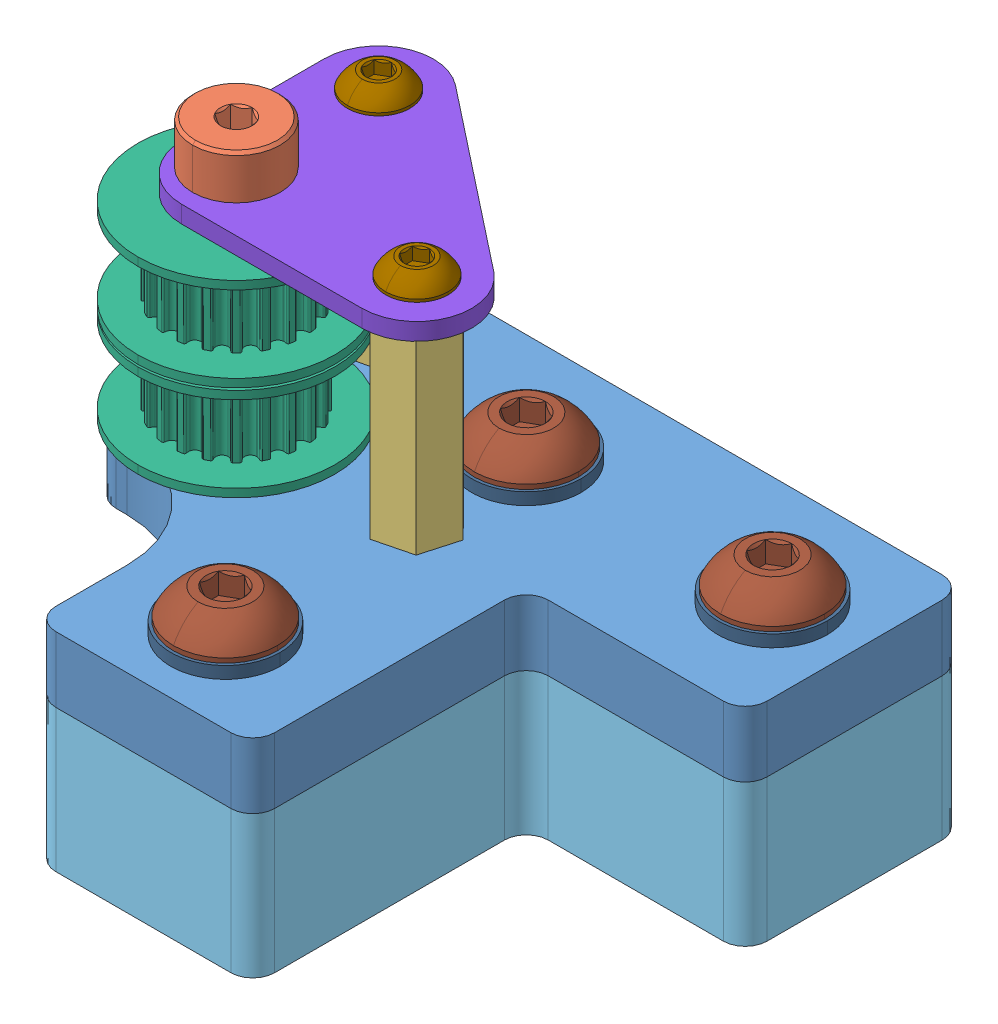
SolidWorks assembly left_double_pulley_corner_bracket_assembly, configuration Default. Lengths in mm.
Overall size (55.5 47.91 45).
24 component instances, 12 part files, 0 mates.
Components (placement in the parent):
- left_double_pulley_corner_bracket_assembly.STEP-1: left_double_pulley_corner_bracket_assembly.STEP [Default] at origin size (55.5 47.91 45)
  - alum_double_pulley_corner_bracketr_Left Double Pulley Corner Bracket.STEP-1: alum_double_pulley_corner_bracketr_Left Double Pulley Corner Bracket.STEP [Default] at (0.7975 43.4223 39.9908) size (53 6 45)
  - m4_shoulder_screw_5mm_d_20mm_l_90278A374_90278A374.STEP-1: m4_shoulder_screw_5mm_d_20mm_l_90278A374_90278A374.STEP [Default] at (7.2975 73.4223 59.9908) x (1 0 0) z (0 1 0) size (8 8 29.01)
  - m3_18mm_hex_standoff_6mm_wide_95947A525_95947A525.STEP-1: m3_18mm_hex_standoff_6mm_wide_95947A525_95947A525.STEP [Default] at (7.2975 58.4223 46.9908) x (0.954641 0 0.297758) z (0 -1 0) size (6 6.93 18)
  - m3_18mm_hex_standoff_6mm_wide_95947A525_95947A525.STEP-2: m3_18mm_hex_standoff_6mm_wide_95947A525_95947A525.STEP [Default] at (23.7975 58.4223 59.9908) x (-0.962053 0 -0.272861) z (0 1 0) size (6 6.93 18)
  - m3_10mm_buttonhead_screw_92095A182_92095A182.STEP-1: m3_10mm_buttonhead_screw_92095A182_92095A182.STEP [Default] at (7.2975 41.7723 46.9908) x (1 0 0) z (0 -1 0) size (5.7 5.7 11.66)
  - m3_10mm_buttonhead_screw_92095A182_92095A182.STEP-2: m3_10mm_buttonhead_screw_92095A182_92095A182.STEP [Default] at (23.7975 41.7723 59.9908) x (1 0 0) z (0 -1 0) size (5.7 5.7 11.66)
  - double_pulley_corner_bracket_Left Machined Bracket Spacer.STEP-1: double_pulley_corner_bracket_Left Machined Bracket Spacer.STEP [Default] at (13.7975 30.4223 84.9908) size (40 13 45)
  - 20t_idler_5mm_bore.STEP-1: 20t_idler_5mm_bore.STEP [Default] at (7.2975 49.6223 59.9908) size (18 8.5 18)
  - 20t_idler_5mm_bore.STEP-2: 20t_idler_5mm_bore.STEP [Default] at (7.2975 58.3223 59.9908) size (18 8.5 18)
  - m5_shim_0.2mm_thick_98089A246_98089A246.STEP-1: m5_shim_0.2mm_thick_98089A246_98089A246.STEP [Default] at (7.2975 49.4223 59.9908) size (10 0.2 10)
  - m5_shim_0.2mm_thick_98089A246_98089A246.STEP-2: m5_shim_0.2mm_thick_98089A246_98089A246.STEP [Default] at (7.2975 58.1223 59.9908) size (10 0.2 10)
  - back_pulley_reinforcement_plate.STEP-1: back_pulley_reinforcement_plate.STEP [Default] at (7.2975 67.4223 59.9908) size (26.5 1.57 23)
  - m3_6mm_buttonhead_screw_92095A179_92095A179.STEP-1: m3_6mm_buttonhead_screw_92095A179_92095A179.STEP [Default] at (7.2975 70.6423 46.9908) x (1 0 0) z (0 1 0) size (5.7 5.7 7.66)
  - m3_6mm_buttonhead_screw_92095A179_92095A179.STEP-2: m3_6mm_buttonhead_screw_92095A179_92095A179.STEP [Default] at (23.7975 70.6423 59.9908) x (1 0 0) z (0 1 0) size (5.7 5.7 7.66)
  - m5_stainless_steel_washer_90965A160_90965A160.STEP-1: m5_stainless_steel_washer_90965A160_90965A160.STEP [Default] at (23.7975 49.4223 77.4908) x (1 0 0) z (0 1 0) size (10 10 1.1)
  - m5_stainless_steel_washer_90965A160_90965A160.STEP-2: m5_stainless_steel_washer_90965A160_90965A160.STEP [Default] at (23.7975 49.4223 49.9908) x (1 0 0) z (0 1 0) size (10 10 1.1)
  - m5_stainless_steel_washer_90965A160_90965A160.STEP-3: m5_stainless_steel_washer_90965A160_90965A160.STEP [Default] at (46.2975 49.4223 49.9908) x (1 0 0) z (0 1 0) size (10 10 1.1)
  - m5_25mm_buttonhead_screw_92095A216_92095A216.STEP-1: m5_25mm_buttonhead_screw_92095A216_92095A216.STEP [Default] at (23.7975 53.2723 77.4908) x (1 0 0) z (0 1 0) size (9.5 9.5 27.76)
  - m5_25mm_buttonhead_screw_92095A216_92095A216.STEP-2: m5_25mm_buttonhead_screw_92095A216_92095A216.STEP [Default] at (23.7975 53.2723 49.9908) x (1 0 0) z (0 1 0) size (9.5 9.5 27.76)
  - m5_25mm_buttonhead_screw_92095A216_92095A216.STEP-3: m5_25mm_buttonhead_screw_92095A216_92095A216.STEP [Default] at (46.2975 53.2723 49.9908) x (1 0 0) z (0 1 0) size (9.5 9.5 27.76)
  - m5_locking_t_nut_20x20_generic.STEP-1: m5_locking_t_nut_20x20_generic.STEP [Default] at (20.7975 25.5223 77.4908) x (0 0 -1) z (1 0 0) size (10 4.5 6)
  - m5_locking_t_nut_20x20_generic.STEP-2: m5_locking_t_nut_20x20_generic.STEP [Default] at (20.7975 25.5223 49.9908) x (0 0 -1) z (1 0 0) size (10 4.5 6)
  - m5_locking_t_nut_20x20_generic.STEP-3: m5_locking_t_nut_20x20_generic.STEP [Default] at (46.2975 25.5223 52.9908) x (-1 0 0) z (0 0 -1) size (10 4.5 6)
